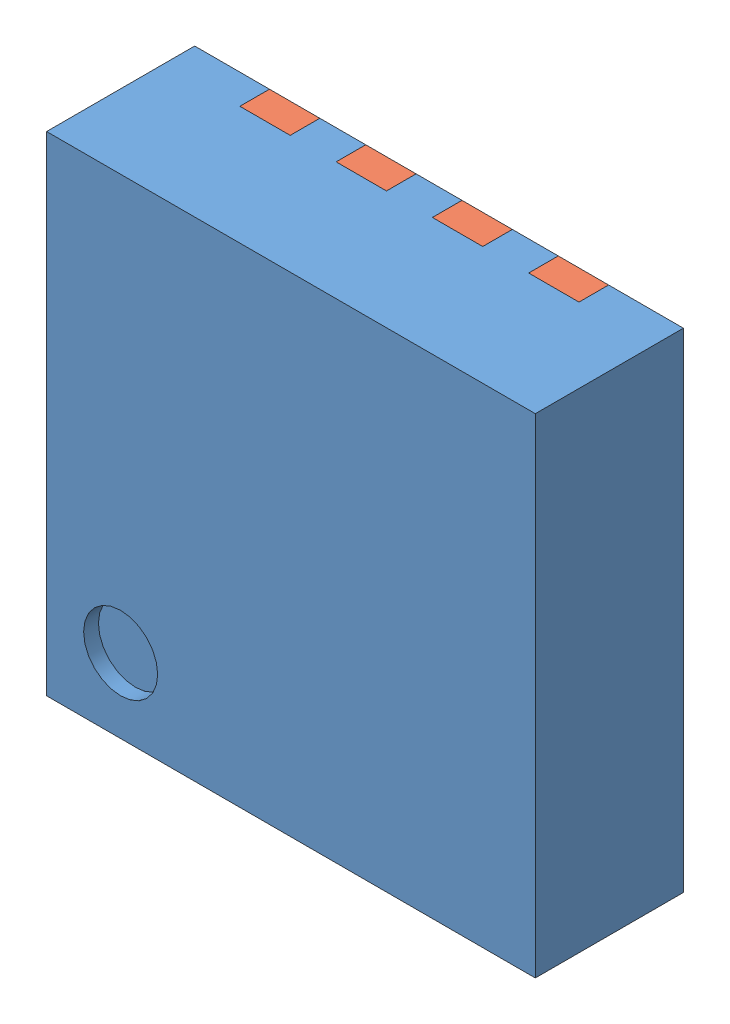
SolidWorks assembly PG-TSDSON-8, configuration По умолчанию. Lengths in mm.
Overall size (3.3 3.3 1).
2 component instances, 2 part files, 4 mates.
Components (placement in the parent):
- PG-TSDSON-8_pack-1: PG-TSDSON-8_pack [По умолчанию] at origin size (3.3 3.3 1)
- PG-TSDSON-8_contacts-1: PG-TSDSON-8_contacts [По умолчанию] at (0 0 0.2) x (-1 0 0) z (0 0 -1) size (2.29 3.3 0.2)
Mates (geometry in assembly coordinates):
- Совпадение3: coordinate: point of PG-TSDSON-8_pack-1
- Совпадение4: coincident: plane of PG-TSDSON-8_pack-1 through (0 0 0.2) normal (0 0 -1); plane of PG-TSDSON-8_contacts-1 through (0 0 0.2) normal (0 0 1)
- Совпадение5: coincident: plane of PG-TSDSON-8_pack-1 through (-1.145 -0.46 0.2) normal (1 0 0); plane of PG-TSDSON-8_contacts-1 through (-1.145 -0.46 0) normal (-1 0 0)
- Совпадение6: coincident: plane of PG-TSDSON-8_pack-1 through (-1.65 1.65 1) normal (0 1 0); plane of PG-TSDSON-8_contacts-1 through (-0.155 1.65 0) normal (0 1 0)
